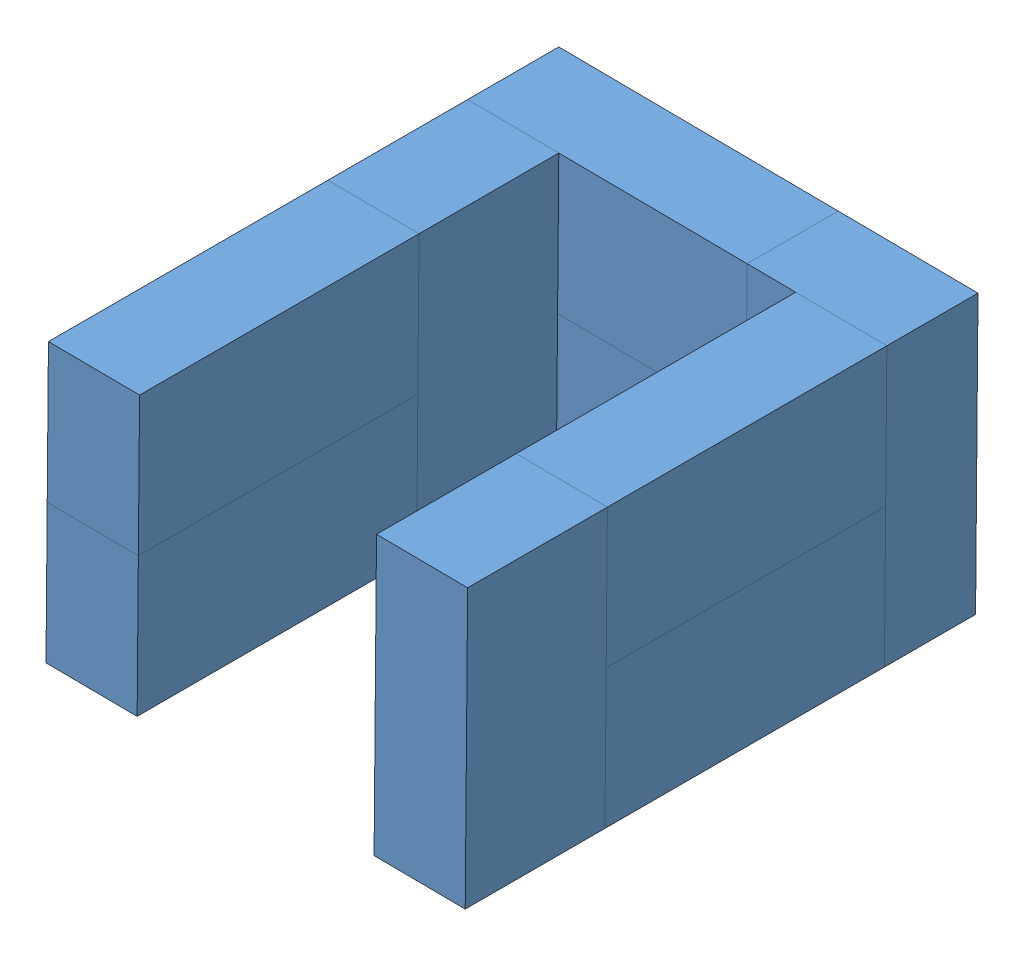
SolidWorks assembly Assem2, configuration Default. Lengths in mm.
Overall size (349.01 234.31 422.01).
12 component instances, 1 part files, 6 mates.
Components (placement in the parent):
- Side Wall-1: Side Wall [Default] at origin size (77 230.65 345)
  - Brick-Whole-1: Brick-Whole [Default] x (-0.008727 -0.999962 0) z (0 0 1) size (230 75 115)
  - Brick-Whole-2: Brick-Whole [Default] at (0.5018 57.4978 -172.5) x (0 0 1) z (0.008727 0.999962 0) size (230 75 115)
  - Brick-Whole-3: Brick-Whole [Default] at (-0.5018 -57.4978 -172.5) x (0 0 1) z (0.008727 0.999962 0) size (230 75 115)
- Side Wall-2: Side Wall [Default] at (-269.9897 2.3562 -230) x (-0.999848 0.017452 0) z (0 0 -1) size (77 230.65 345)
  - Brick-Whole-1: Brick-Whole [Default] x (-0.008727 -0.999962 0) z (0 0 1) size (230 75 115)
  - Brick-Whole-2: Brick-Whole [Default] at (0.5018 57.4978 -172.5) x (0 0 1) z (0.008727 0.999962 0) size (230 75 115)
  - Brick-Whole-3: Brick-Whole [Default] at (-0.5018 -57.4978 -172.5) x (0 0 1) z (0.008727 0.999962 0) size (230 75 115)
- Side Wall-3: Side Wall [Default] at (-19.9992 0.1745 -325) x (0.000076 0.008726 -0.999962) z (0.999962 -0.008727 0) size (77 230.65 345)
  - Brick-Whole-1: Brick-Whole [Default] x (-0.008727 -0.999962 0) z (0 0 1) size (230 75 115)
  - Brick-Whole-2: Brick-Whole [Default] at (0.5018 57.4978 -172.5) x (0 0 1) z (0.008727 0.999962 0) size (230 75 115)
  - Brick-Whole-3: Brick-Whole [Default] at (-0.5018 -57.4978 -172.5) x (0 0 1) z (0.008727 0.999962 0) size (230 75 115)
Mates (geometry in assembly coordinates):
- Coincident8: coincident: plane of Side Wall-1/Brick-Whole-2 through (37.4986 -0.3272 -287.5) normal (0 0 -1); plane of Side Wall-3/Brick-Whole-1 through (-19.9992 0.1745 -287.5) normal (0 0 1)
- Coincident9: coincident: line of Side Wall-1/Brick-Whole-3 through (36.495 -115.3229 -287.5) axis (-0.999962 0.008727 0); line of Side Wall-3/Brick-Whole-1 through (36.495 -115.3229 -287.5) axis (-0.999962 0.008727 0)
- Coincident10: coincident anti-aligned: line of Side Wall-1/Brick-Whole-2 through (37.4986 -0.3272 -287.5) axis (0.008727 0.999962 0); line of Side Wall-3/Brick-Whole-1 through (38.5021 114.6684 -287.5) axis (-0.008727 -0.999962 0)
- Coincident11: coincident: plane of Side Wall-2/Brick-Whole-1 through (-306.4847 117.679 -287.5) normal (0 0 -1); plane of Side Wall-3/Brick-Whole-3 through (-192.9944 -55.818 -287.5) normal (0 0 1)
- Coincident12: coincident: line of Side Wall-2/Brick-Whole-1 through (-308.4918 -112.3122 -287.5) axis (0 0 1); line of Side Wall-3/Brick-Whole-3 through (-308.4918 -112.3122 -362.5) axis (0 0 1)
- Coincident13: coincident anti-aligned: line of Side Wall-2/Brick-Whole-1 through (-306.4847 117.679 -172.5) axis (0 0 -1); line of Side Wall-3/Brick-Whole-2 through (-306.4847 117.679 -362.5) axis (0 0 1)
